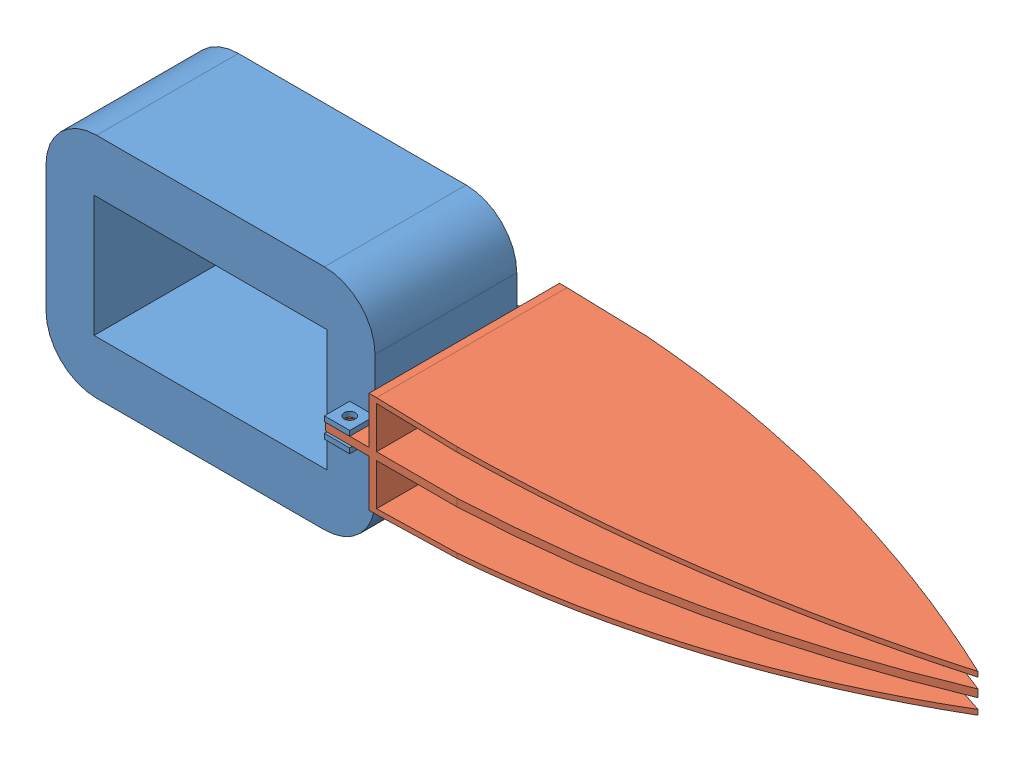
SolidWorks assembly busassembly, configuration 預設. Lengths in mm.
Overall size (170.1 45 38.13).
2 component instances, 2 part files, 3 mates.
Components (placement in the parent):
- bustail-1: bustail [預設] at (20.0058 1.6659 51) size (65 45 38)
- tail-1: tail [預設] at (29.173 1.7277 64.2648) x (1 0 0) z (0 -1 0) size (110.1 38.13 22.65)
Mates (geometry in assembly coordinates):
- 重合/共線/共點2: coincident: plane of bustail-1 through (20.0058 1.6659 84) normal (0 0 1); plane of tail-1 through (20.0711 2.3809 84) normal (0 0 1)
- 重合/共線/共點3: coincident: plane of bustail-1 through (20.0058 1.6659 46) normal (0 0 -1); plane of tail-1 through (20.0711 2.4777 46) normal (0 0 -1)
- 同軸心1: concentric: cylinder of bustail-1 through (22.5711 4.6659 48.5) axis (0 -1 0) radius 1.1; cylinder of tail-1 through (22.5711 2.4777 48.5) axis (0 -1 0) radius 1.1
